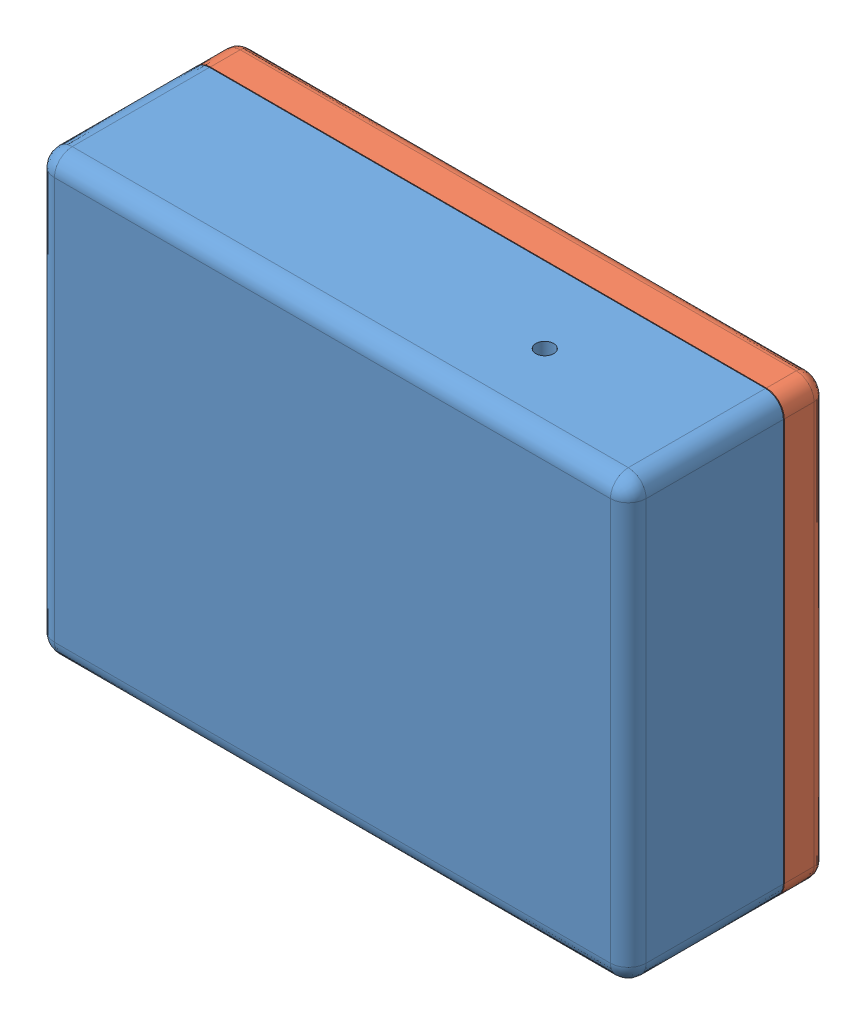
SolidWorks assembly Assem4, configuration Default. Lengths in mm.
Overall size (99.22 73.44 33.11).
5 component instances, 3 part files, 0 mates.
Components (placement in the parent):
- Part7^PCB_Audio Output.step-1: Part7^PCB_Audio Output.step [Default] at (-298.4205 299.0534 83.8862) size (99.18 73.43 26)
- Part8^PCB_Audio Output.step. v1SLDPRT-1: Part8^PCB_Audio Output.step. v1SLDPRT [Default] at (-466.3145 441.9931 67.7782) x (1 0 0) z (0 0 -1) size (99.18 73.43 7)
- PCB_Audio Output.step-1: PCB_Audio Output.step [Default] at (-298.4279 299.0582 82.8601) x (-0.999995 0 0.003185) z (-0.003185 0.002436 -0.999992) size (93.18 67.43 0.41)
  - Board.step-1: Board.step [Default] at origin size (93.18 67.43 0.41)
    - Open CASCADE STEP translator 6.8 1.1.1.step-1: Open CASCADE STEP translator 6.8 1.1.1.step [Default] at (0 0 -0.4115) size (93.18 67.43 0.41)
